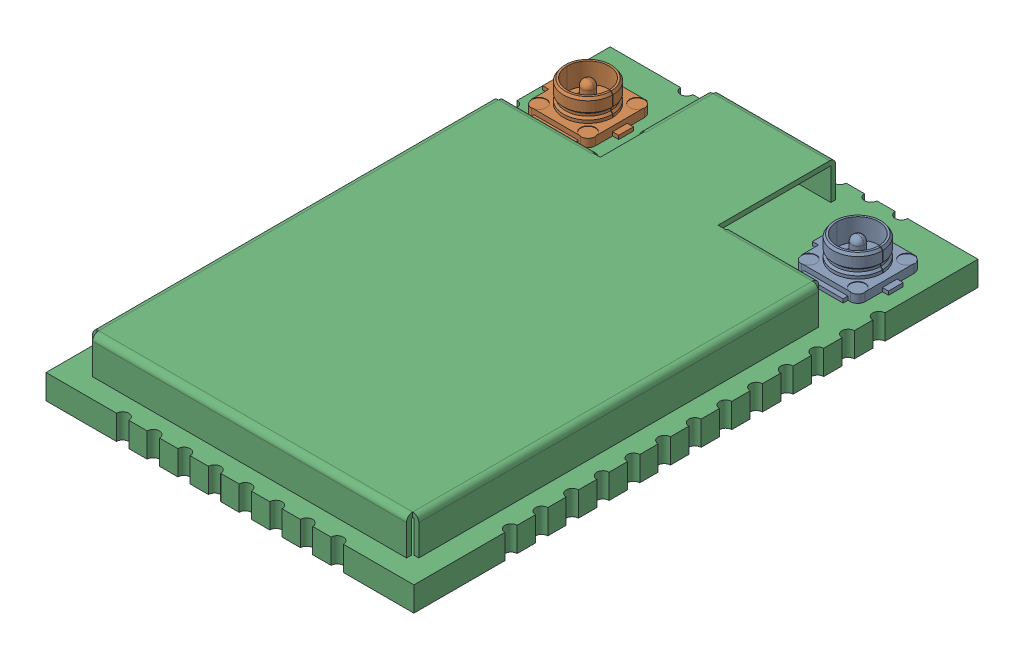
SolidWorks assembly PWB-RAK4600, configuration Predeterminado. Lengths in mm.
Overall size (15 2.5 23).
3 component instances, 2 part files, 0 mates.
Components (placement in the parent):
- IPEX-FEMALE-1: IPEX-FEMALE [Predeterminado] at (12.05 -1.5 -19.4) x (0 0 -1) z (1 0 0) size (3 1.25 3.1)
- IPEX-FEMALE-2: IPEX-FEMALE [Predeterminado] at (1.05 -1.5 -19.4) x (0 0 -1) z (1 0 0) size (3 1.25 3.1)
- 6310C00F_RAK4600-1: 6310C00F_RAK4600 [Predeterminado] at origin size (15 2.5 23)
